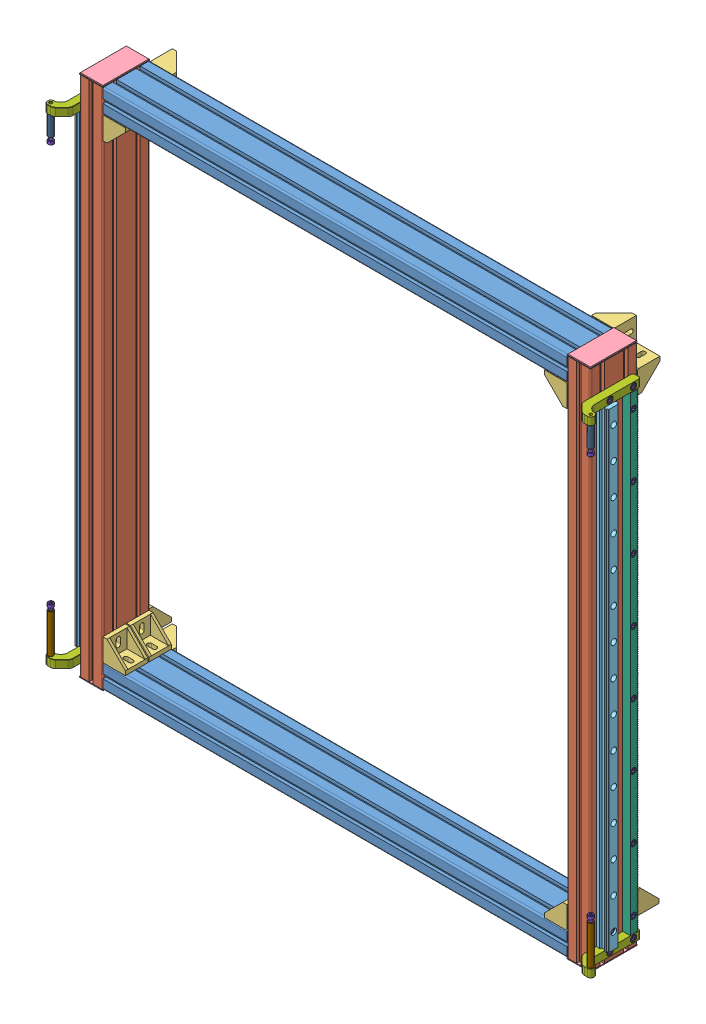
SolidWorks assembly Frame Top Stage, configuration Défaut. Lengths in mm.
Overall size (1047.13 1003 167.07).
94 component instances, 10 part files, 181 mates.
Components (placement in the parent):
- Frame X Top-1: Frame X Top [Défaut] at (-67 22.5 45) x (0 1 0) z (-1 0 0) size (45 90 888)
- Frame Y Top-1: Frame Y Top [Défaut] at (-3.2889 -2 75.8154) x (-1 0 0) z (0 -1 0) size (45 90 998)
- Frame X Top-2: Frame X Top [Défaut] at (-67 975.5 45) x (0 1 0) z (-1 0 0) size (45 90 888)
- Frame Y Top-2: Frame Y Top [Défaut] at (929.7111 -2 75.8154) x (-1 0 0) z (0 -1 0) size (45 90 998)
- nervure-1: nervure [Default] at (45 45 47) size (43 43 43)
- nervure-2: nervure [Default] at (45 953 47) x (0 -1 0) z (0 0 1) size (43 43 43)
- nervure-3: nervure [Default] at (933 45 47) x (0 1 0) z (0 0 1) size (43 43 43)
- nervure-4: nervure [Default] at (933 953 47) x (-1 0 0) z (0 0 1) size (43 43 43)
- nervure-5: nervure [Default] at (45 953 2) x (0 -1 0) z (0 0 1) size (43 43 43)
- nervure-6: nervure [Default] at (933 953 2) x (-1 0 0) z (0 0 1) size (43 43 43)
- nervure-7: nervure [Default] at (933 45 2) x (0 1 0) z (0 0 1) size (43 43 43)
- nervure-8: nervure [Default] at (45 45 2) size (43 43 43)
- Alu Profile End Cap 45x90-1: Alu Profile End Cap 45x90 [Défaut] at (22.5 0 45) x (0 0 1) z (0 -1 0) size (90 45 12.5)
- Alu Profile End Cap 45x90-5: Alu Profile End Cap 45x90 [Défaut] at (22.5 998 45) x (0 0 1) z (0 1 0) size (90 45 12.5)
- Alu Profile End Cap 45x90-6: Alu Profile End Cap 45x90 [Défaut] at (955.5 998 45) x (0 0 1) z (0 1 0) size (90 45 12.5)
- Alu Profile End Cap 45x90-4: Alu Profile End Cap 45x90 [Défaut] at (955.5 0 45) x (0 0 1) z (0 -1 0) size (90 45 12.5)
- nervure-9: nervure [Default] at (45 0 0) x (1 0 0) z (0 1 0) size (43 43 43)
- nervure-10: nervure [Default] at (43 45 0) x (0 1 0) z (-1 0 0) size (43 43 43)
- nervure-11: nervure [Default] at (933 45 0) x (-1 0 0) z (0 -1 0) size (43 43 43)
- nervure-12: nervure [Default] at (976 45 0) x (0 1 0) z (-1 0 0) size (43 43 43)
- nervure-13: nervure [Default] at (935 953 0) x (0 -1 0) z (1 0 0) size (43 43 43)
- nervure-14: nervure [Default] at (933 998 0) x (-1 0 0) z (0 -1 0) size (43 43 43)
- nervure-15: nervure [Default] at (2 953 0) x (0 -1 0) z (1 0 0) size (43 43 43)
- nervure-16: nervure [Default] at (45 953 0) x (1 0 0) z (0 1 0) size (43 43 43)
- HGR25-R1000-1: HGR25-R1000 [Default] at (989 485.5 67.5) x (0 0 -1) z (0 -1 0) size (23 22 900)
- Rack-2: Rack [Défaut] at (993 931.8745 23.75) x (0 1 0) z (-1 0 0) size (899.02 15 15)
- HGR25-R1000-2: HGR25-R1000 [Default] at (-11 485.5 67.5) x (0 0 -1) z (0 1 0) size (23 22 900)
- Y Axis Stop-1: Y Axis Stop [Défaut] at (979.0859 950.5 84.2092) x (1 0 0) z (0 -1 0) size (34 114.75 15)
- Y Axis Stop-2: Y Axis Stop [Défaut] at (979.0859 35.5 84.2092) x (1 0 0) z (0 -1 0) size (34 114.75 15)
- Y Axis Stop-3: Y Axis Stop [Défaut] at (-1.0859 935.5 84.2092) x (-1 0 0) z (0 1 0) size (34 114.75 15)
- Y Axis Stop-4: Y Axis Stop [Défaut] at (-1.0859 20.5 84.2092) x (-1 0 0) z (0 1 0) size (34 114.75 15)
- socket head cap screw_am-2: socket head cap screw_am [B18.3.1M - 6 x 1.0 x 16 Hex SHCS -- 16NHX] at (-27.5 883 117) x (0 1 0) z (0 0 1) size (22 10 10)
- socket head cap screw_am-3: socket head cap screw_am [B18.3.1M - 6 x 1.0 x 16 Hex SHCS -- 16NHX] at (-27.5 122 117) x (0 -1 0) z (0.064917 0 0.997891) size (22 10 10)
- socket head cap screw_am-4: socket head cap screw_am [B18.3.1M - 6 x 1.0 x 16 Hex SHCS -- 16NHX] at (1005.5 122 117) x (0 -1 0) z (0 0 1) size (22 10 10)
- socket head cap screw_am-5: socket head cap screw_am [B18.3.1M - 6 x 1.0 x 16 Hex SHCS -- 16NHX] at (1005.5 883 117) x (0 1 0) z (0 0 1) size (22 10 10)
- Rack-5: Rack [Défaut] at (-15 39.1255 23.75) x (0 -1 0) z (1 0 0) size (899.02 15 15)
- socket head cap screw_am-6: socket head cap screw_am [B18.3.1M - 6 x 1.0 x 10 Hex SHCS -- 10NHX] at (997 65.5 67.5) x (-1 0 0) z (0 0.924225 0.381849) size (16 10 10)
- socket head cap screw_am-7: socket head cap screw_am [B18.3.1M - 6 x 1.0 x 10 Hex SHCS -- 10NHX] at (997 125.5 67.5) x (-1 0 0) z (0 0.924225 0.381849) size (16 10 10)
- socket head cap screw_am-8: socket head cap screw_am [B18.3.1M - 6 x 1.0 x 10 Hex SHCS -- 10NHX] at (997 185.5 67.5) x (-1 0 0) z (0 0.924225 0.381849) size (16 10 10)
- socket head cap screw_am-9: socket head cap screw_am [B18.3.1M - 6 x 1.0 x 10 Hex SHCS -- 10NHX] at (997 245.5 67.5) x (-1 0 0) z (0 0.924225 0.381849) size (16 10 10)
- socket head cap screw_am-10: socket head cap screw_am [B18.3.1M - 6 x 1.0 x 10 Hex SHCS -- 10NHX] at (997 305.5 67.5) x (-1 0 0) z (0 0.924225 0.381849) size (16 10 10)
- socket head cap screw_am-11: socket head cap screw_am [B18.3.1M - 6 x 1.0 x 10 Hex SHCS -- 10NHX] at (997 365.5 67.5) x (-1 0 0) z (0 0.924225 0.381849) size (16 10 10)
- socket head cap screw_am-12: socket head cap screw_am [B18.3.1M - 6 x 1.0 x 10 Hex SHCS -- 10NHX] at (997 425.5 67.5) x (-1 0 0) z (0 0.924225 0.381849) size (16 10 10)
- socket head cap screw_am-13: socket head cap screw_am [B18.3.1M - 6 x 1.0 x 10 Hex SHCS -- 10NHX] at (997 485.5 67.5) x (-1 0 0) z (0 0.924225 0.381849) size (16 10 10)
- socket head cap screw_am-14: socket head cap screw_am [B18.3.1M - 6 x 1.0 x 10 Hex SHCS -- 10NHX] at (997 545.5 67.5) x (-1 0 0) z (0 0.924225 0.381849) size (16 10 10)
- socket head cap screw_am-15: socket head cap screw_am [B18.3.1M - 6 x 1.0 x 10 Hex SHCS -- 10NHX] at (997 605.5 67.5) x (-1 0 0) z (0 0.924225 0.381849) size (16 10 10)
- socket head cap screw_am-16: socket head cap screw_am [B18.3.1M - 6 x 1.0 x 10 Hex SHCS -- 10NHX] at (997 665.5 67.5) x (-1 0 0) z (0 0.924225 0.381849) size (16 10 10)
- socket head cap screw_am-17: socket head cap screw_am [B18.3.1M - 6 x 1.0 x 10 Hex SHCS -- 10NHX] at (997 725.5 67.5) x (-1 0 0) z (0 0.924225 0.381849) size (16 10 10)
- socket head cap screw_am-18: socket head cap screw_am [B18.3.1M - 6 x 1.0 x 10 Hex SHCS -- 10NHX] at (997 785.5 67.5) x (-1 0 0) z (0 0.924225 0.381849) size (16 10 10)
- socket head cap screw_am-19: socket head cap screw_am [B18.3.1M - 6 x 1.0 x 10 Hex SHCS -- 10NHX] at (997 845.5 67.5) x (-1 0 0) z (0 0.924225 0.381849) size (16 10 10)
- socket head cap screw_am-20: socket head cap screw_am [B18.3.1M - 6 x 1.0 x 10 Hex SHCS -- 10NHX] at (997 905.5 67.5) x (-1 0 0) z (0 0.978734 0.205133) size (16 10 10)
- socket head cap screw_am-21: socket head cap screw_am [B18.3.1M - 6 x 1.0 x 10 Hex SHCS -- 10NHX] at (-19 65.5 67.5) size (16 10 10)
- socket head cap screw_am-22: socket head cap screw_am [B18.3.1M - 6 x 1.0 x 10 Hex SHCS -- 10NHX] at (-19 125.5 67.5) size (16 10 10)
- socket head cap screw_am-23: socket head cap screw_am [B18.3.1M - 6 x 1.0 x 10 Hex SHCS -- 10NHX] at (-19 185.5 67.5) size (16 10 10)
- socket head cap screw_am-24: socket head cap screw_am [B18.3.1M - 6 x 1.0 x 10 Hex SHCS -- 10NHX] at (-19 245.5 67.5) size (16 10 10)
- socket head cap screw_am-25: socket head cap screw_am [B18.3.1M - 6 x 1.0 x 10 Hex SHCS -- 10NHX] at (-19 305.5 67.5) size (16 10 10)
- socket head cap screw_am-26: socket head cap screw_am [B18.3.1M - 6 x 1.0 x 10 Hex SHCS -- 10NHX] at (-19 365.5 67.5) size (16 10 10)
- socket head cap screw_am-27: socket head cap screw_am [B18.3.1M - 6 x 1.0 x 10 Hex SHCS -- 10NHX] at (-19 425.5 67.5) size (16 10 10)
- socket head cap screw_am-28: socket head cap screw_am [B18.3.1M - 6 x 1.0 x 10 Hex SHCS -- 10NHX] at (-19 485.5 67.5) size (16 10 10)
- socket head cap screw_am-29: socket head cap screw_am [B18.3.1M - 6 x 1.0 x 10 Hex SHCS -- 10NHX] at (-19 545.5 67.5) size (16 10 10)
- socket head cap screw_am-30: socket head cap screw_am [B18.3.1M - 6 x 1.0 x 10 Hex SHCS -- 10NHX] at (-19 605.5 67.5) size (16 10 10)
- socket head cap screw_am-31: socket head cap screw_am [B18.3.1M - 6 x 1.0 x 10 Hex SHCS -- 10NHX] at (-19 665.5 67.5) size (16 10 10)
- socket head cap screw_am-32: socket head cap screw_am [B18.3.1M - 6 x 1.0 x 10 Hex SHCS -- 10NHX] at (-19 725.5 67.5) size (16 10 10)
- socket head cap screw_am-33: socket head cap screw_am [B18.3.1M - 6 x 1.0 x 10 Hex SHCS -- 10NHX] at (-19 785.5 67.5) size (16 10 10)
- socket head cap screw_am-34: socket head cap screw_am [B18.3.1M - 6 x 1.0 x 10 Hex SHCS -- 10NHX] at (-19 845.5 67.5) size (16 10 10)
- socket head cap screw_am-35: socket head cap screw_am [B18.3.1M - 6 x 1.0 x 10 Hex SHCS -- 10NHX] at (-19 905.5 67.5) x (1 0 0) z (0 -0.994502 0.104716) size (16 10 10)
- socket head cap screw_am-36: socket head cap screw_am [B18.3.1M - 6 x 1.0 x 16 Hex SHCS -- 16NHX] at (-14.6 65.0096 22.5) size (22 10 10)
- socket head cap screw_am-37: socket head cap screw_am [B18.3.1M - 6 x 1.0 x 16 Hex SHCS -- 16NHX] at (-14.6 185.0096 22.5) size (22 10 10)
- socket head cap screw_am-38: socket head cap screw_am [B18.3.1M - 6 x 1.0 x 16 Hex SHCS -- 16NHX] at (-14.6 305.0096 22.5) size (22 10 10)
- socket head cap screw_am-39: socket head cap screw_am [B18.3.1M - 6 x 1.0 x 16 Hex SHCS -- 16NHX] at (-14.6 425.0096 22.5) size (22 10 10)
- socket head cap screw_am-40: socket head cap screw_am [B18.3.1M - 6 x 1.0 x 16 Hex SHCS -- 16NHX] at (-14.6 545.0096 22.5) size (22 10 10)
- socket head cap screw_am-41: socket head cap screw_am [B18.3.1M - 6 x 1.0 x 16 Hex SHCS -- 16NHX] at (-14.6 665.0096 22.5) size (22 10 10)
- socket head cap screw_am-42: socket head cap screw_am [B18.3.1M - 6 x 1.0 x 16 Hex SHCS -- 16NHX] at (-14.6 785.0096 22.5) size (22 10 10)
- socket head cap screw_am-43: socket head cap screw_am [B18.3.1M - 6 x 1.0 x 16 Hex SHCS -- 16NHX] at (-14.6 905.0096 22.5) x (1 0 0) z (0 0.560816 0.82794) size (22 10 10)
- socket head cap screw_am-44: socket head cap screw_am [B18.3.1M - 6 x 1.0 x 16 Hex SHCS -- 16NHX] at (-14.6 943 22.5) size (22 10 10)
- socket head cap screw_am-45: socket head cap screw_am [B18.3.1M - 6 x 1.0 x 16 Hex SHCS -- 16NHX] at (-14.6 943 67.5) size (22 10 10)
- socket head cap screw_am-46: socket head cap screw_am [B18.3.1M - 6 x 1.0 x 16 Hex SHCS -- 16NHX] at (-14.6 28 67.5) size (22 10 10)
- socket head cap screw_am-47: socket head cap screw_am [B18.3.1M - 6 x 1.0 x 16 Hex SHCS -- 16NHX] at (-14.6 28 22.5) size (22 10 10)
- socket head cap screw_am-48: socket head cap screw_am [B18.3.1M - 6 x 1.0 x 16 Hex SHCS -- 16NHX] at (992.6 943 67.5) x (-1 0 0) z (0 0.924225 0.381849) size (22 10 10)
- socket head cap screw_am-49: socket head cap screw_am [B18.3.1M - 6 x 1.0 x 16 Hex SHCS -- 16NHX] at (992.6 943 22.5) x (-1 0 0) z (0 0.924225 0.381849) size (22 10 10)
- socket head cap screw_am-50: socket head cap screw_am [B18.3.1M - 6 x 1.0 x 16 Hex SHCS -- 16NHX] at (992.6 905.9904 22.5) x (-1 0 0) z (0 0.924225 0.381849) size (22 10 10)
- socket head cap screw_am-51: socket head cap screw_am [B18.3.1M - 6 x 1.0 x 16 Hex SHCS -- 16NHX] at (992.6 785.9904 22.5) x (-1 0 0) z (0 0.924225 0.381849) size (22 10 10)
- socket head cap screw_am-52: socket head cap screw_am [B18.3.1M - 6 x 1.0 x 16 Hex SHCS -- 16NHX] at (992.6 665.9904 22.5) x (-1 0 0) z (0 0.924225 0.381849) size (22 10 10)
- socket head cap screw_am-53: socket head cap screw_am [B18.3.1M - 6 x 1.0 x 16 Hex SHCS -- 16NHX] at (992.6 545.9904 22.5) x (-1 0 0) z (0 0.924225 0.381849) size (22 10 10)
- socket head cap screw_am-54: socket head cap screw_am [B18.3.1M - 6 x 1.0 x 16 Hex SHCS -- 16NHX] at (992.6 425.9904 22.5) x (-1 0 0) z (0 0.924225 0.381849) size (22 10 10)
- socket head cap screw_am-55: socket head cap screw_am [B18.3.1M - 6 x 1.0 x 16 Hex SHCS -- 16NHX] at (992.6 305.9904 22.5) x (-1 0 0) z (0 0.924225 0.381849) size (22 10 10)
- socket head cap screw_am-56: socket head cap screw_am [B18.3.1M - 6 x 1.0 x 16 Hex SHCS -- 16NHX] at (992.6 185.9904 22.5) x (-1 0 0) z (0 0.924225 0.381849) size (22 10 10)
- socket head cap screw_am-57: socket head cap screw_am [B18.3.1M - 6 x 1.0 x 16 Hex SHCS -- 16NHX] at (992.6 65.9904 22.5) x (-1 0 0) z (0 0.924225 0.381849) size (22 10 10)
- socket head cap screw_am-58: socket head cap screw_am [B18.3.1M - 6 x 1.0 x 16 Hex SHCS -- 16NHX] at (992.6 28 67.5) x (-1 0 0) z (0 0.924225 0.381849) size (22 10 10)
- socket head cap screw_am-59: socket head cap screw_am [B18.3.1M - 6 x 1.0 x 16 Hex SHCS -- 16NHX] at (992.6 28 22.5) x (-1 0 0) z (0 0.924225 0.381849) size (22 10 10)
- EndStop Spacer 75mm-1: EndStop Spacer 75mm [Défaut] at (1005.5 35.5 117) x (0.737077 0 0.675809) z (0 1 0) size (10 10 85)
- EndStop Spacer 40mm-1: EndStop Spacer 40mm [Défaut] at (-27.5 935.5 117) x (-0.718383 0 -0.695648) z (0 -1 0) size (10 10 50)
- EndStop Spacer 75mm-2: EndStop Spacer 75mm [Défaut] at (-27.5 35.5 117) x (1 0 0) z (0 1 0) size (10 10 85)
- EndStop Spacer 40mm-2: EndStop Spacer 40mm [Défaut] at (1005.5 935.5 117) x (1 0 0) z (0 -1 0) size (10 10 50)
Mates (geometry in assembly coordinates):
- Coïncidente1: coincident anti-aligned: plane of Frame X Top-1 through (45 0 63.5) normal (0 -1 0); plane of assembly through (0 0 0) normal (0 1 0)
- Coïncidente2: coincident anti-aligned: plane of Frame X Top-1 through (45 3 0) normal (0 0 -1); plane of assembly through (0 0 0) normal (0 0 1)
- Distance1: distance = 45 mm: plane of assembly through (0 0 0) normal (1 0 0); plane of assembly; plane of Frame X Top-1 through (45 3 87) normal (-1 0 0)
- Coïncidente3: coincident aligned: plane of Frame X Top-1 through (45 0 63.5) normal (0 -1 0); plane of Frame Y Top-1 through (42 0 87) normal (0 -1 0)
- Coïncidente4: coincident aligned: plane of Frame X Top-1 through (45 42 90) normal (0 0 1); plane of Frame Y Top-1 through (26.5 0 90) normal (0 0 1)
- Coïncidente5: coincident anti-aligned: plane of Frame X Top-1 through (45 3 87) normal (-1 0 0); plane of Frame Y Top-1 through (45 0 63.5) normal (1 0 0)
- Coïncidente6: coincident aligned: plane of Frame X Top-1 through (45 18.5 90) normal (0 0 1); plane of Frame X Top-2 through (45 971.5 90) normal (0 0 1)
- Coïncidente7: coincident aligned: plane of Frame X Top-1 through (933 3 87) normal (1 0 0); plane of Frame X Top-2 through (933 956 87) normal (1 0 0)
- Coïncidente8: coincident aligned: plane of Frame X Top-1 through (45 18.5 90) normal (0 0 1); plane of Frame Y Top-2 through (936 0 90) normal (0 0 1)
- Coïncidente9: coincident aligned: plane of Frame X Top-1 through (45 0 63.5) normal (0 -1 0); plane of Frame Y Top-2 through (975 0 87) normal (0 -1 0)
- Coïncidente10: coincident anti-aligned: plane of Frame X Top-1 through (933 3 87) normal (1 0 0); plane of Frame Y Top-2 through (933 0 26.5) normal (-1 0 0)
- Coïncidente11: coincident aligned: plane of Frame X Top-2 through (45 998 26.5) normal (0 1 0); plane of Frame Y Top-2 through (975 998 87) normal (0 1 0)
- Coïncidente12: coincident aligned: plane of Frame X Top-1 through (45 42 90) normal (0 0 1); plane of nervure-1 through (45 45 90) normal (0 0 1)
- Coïncidente13: coincident anti-aligned: plane of Frame Y Top-1 through (45 0 87) normal (1 0 0); plane of nervure-1 through (45 88 90) normal (-1 0 0)
- Coïncidente14: coincident anti-aligned: plane of Frame X Top-1 through (45 45 71.5) normal (0 1 0); plane of nervure-1 through (45 45 90) normal (0 -1 0)
- Coïncidente15: coincident aligned: plane of Frame X Top-1 through (45 42 90) normal (0 0 1); plane of nervure-3 through (933 45 90) normal (0 0 1)
- Coïncidente16: coincident aligned: plane of Frame X Top-1 through (45 42 90) normal (0 0 1); plane of nervure-2 through (45 953 90) normal (0 0 1)
- Coïncidente17: coincident aligned: plane of Frame X Top-1 through (45 42 90) normal (0 0 1); plane of nervure-4 through (933 953 90) normal (0 0 1)
- Coïncidente18: coincident anti-aligned: plane of Frame Y Top-2 through (933 0 26.5) normal (-1 0 0); plane of nervure-3 through (933 45 90) normal (1 0 0)
- Coïncidente19: coincident anti-aligned: plane of Frame Y Top-2 through (933 0 26.5) normal (-1 0 0); plane of nervure-4 through (933 910 90) normal (1 0 0)
- Coïncidente20: coincident anti-aligned: plane of Frame X Top-2 through (45 953 63.5) normal (0 -1 0); plane of nervure-2 through (88 953 90) normal (0 1 0)
- Coïncidente21: coincident anti-aligned: plane of Frame X Top-2 through (45 953 63.5) normal (0 -1 0); plane of nervure-4 through (933 953 90) normal (0 1 0)
- Coïncidente22: coincident anti-aligned: plane of Frame X Top-1 through (45 45 26.5) normal (0 1 0); plane of nervure-3 through (890 45 90) normal (0 -1 0)
- Coïncidente23: coincident anti-aligned: plane of Frame Y Top-1 through (45 0 63.5) normal (1 0 0); plane of nervure-2 through (45 953 90) normal (-1 0 0)
- Coïncidente24: coincident anti-aligned: plane of Frame Y Top-1 through (42 0 87) normal (0 -1 0); plane of Alu Profile End Cap 45x90-1 through (22.5 0 45) normal (0 1 0)
- Coaxiale1: concentric anti-aligned: cylinder of Frame Y Top-1 through (22.5 0 67.5) axis (0 1 0) radius 4; cylinder of Alu Profile End Cap 45x90-1 through (22.5 10 67.5) axis (0 -1 0) radius 4
- Coaxiale2: concentric anti-aligned: cylinder of Frame Y Top-1 through (22.5 0 22.5) axis (0 1 0) radius 4; cylinder of Alu Profile End Cap 45x90-1 through (22.5 10 22.5) axis (0 -1 0) radius 4
- Coïncidente25: coincident anti-aligned: plane of Frame Y Top-1 through (42 998 87) normal (0 1 0); plane of Alu Profile End Cap 45x90-5 through (22.5 998 45) normal (0 -1 0)
- Coaxiale3: concentric aligned: cylinder of Frame Y Top-1 through (22.5 0 67.5) axis (0 1 0) radius 4; cylinder of Alu Profile End Cap 45x90-5 through (22.5 988 67.5) axis (0 1 0) radius 4
- Coaxiale4: concentric aligned: cylinder of Frame Y Top-1 through (22.5 0 22.5) axis (0 1 0) radius 4; cylinder of Alu Profile End Cap 45x90-5 through (22.5 988 22.5) axis (0 1 0) radius 4
- Coïncidente26: coincident anti-aligned: plane of Frame X Top-1 through (45 26.5 0) normal (0 0 -1); plane of nervure-9 through (45 43 0) normal (0 0 1)
- Coïncidente27: coincident anti-aligned: plane of Frame X Top-1 through (45 26.5 0) normal (0 0 -1); plane of nervure-10 through (0 45 0) normal (0 0 1)
- Coïncidente28: coincident aligned: plane of Frame X Top-1 through (45 0 18.5) normal (0 -1 0); plane of nervure-9 through (45 0 0) normal (0 -1 0)
- Coïncidente29: coincident anti-aligned: plane of Frame Y Top-1 through (45 0 63.5) normal (1 0 0); plane of nervure-9 through (45 43 -43) normal (-1 0 0)
- Coïncidente30: coincident anti-aligned: plane of Frame X Top-1 through (45 45 26.5) normal (0 1 0); plane of nervure-10 through (0 45 -43) normal (0 -1 0)
- Coïncidente31: coincident aligned: plane of Frame Y Top-1 through (0 0 26.5) normal (-1 0 0); plane of nervure-10 through (0 45 0) normal (-1 0 0)
- Coïncidente32: coincident anti-aligned: plane of Frame X Top-1 through (45 3 0) normal (0 0 -1); plane of nervure-12 through (933 45 0) normal (0 0 1)
- Coïncidente33: coincident anti-aligned: plane of Frame X Top-1 through (45 3 0) normal (0 0 -1); plane of nervure-11 through (933 2 0) normal (0 0 1)
- Coïncidente34: coincident aligned: plane of Frame Y Top-2 through (933 0 26.5) normal (-1 0 0); plane of nervure-12 through (933 45 0) normal (-1 0 0)
- Coïncidente35: coincident anti-aligned: plane of Frame X Top-1 through (45 45 26.5) normal (0 1 0); plane of nervure-12 through (933 45 -43) normal (0 -1 0)
- Coïncidente36: coincident aligned: plane of Frame X Top-1 through (45 45 26.5) normal (0 1 0); plane of nervure-11 through (933 45 0) normal (0 1 0)
- Coïncidente37: coincident anti-aligned: plane of Frame Y Top-2 through (933 0 26.5) normal (-1 0 0); plane of nervure-11 through (933 2 -43) normal (1 0 0)
- Coïncidente39: coincident anti-aligned: plane of Frame Y Top-2 through (978 0 63.5) normal (1 0 0); plane of HGR25-R1000-1 through (978 -14.5 78) normal (-1 0 0)
- Largeur2: width anti-aligned: plane of HGR25-R1000-1 through (979 -14.5 56) normal (0 0 -1); plane of Frame Y Top-2 through (984 -14.5 79) normal (0 0 1); plane of HGR25-R1000-1 through (972 0 63.5) normal (0 0 1); plane of Frame Y Top-2 through (978 0 71.5) normal (0 0 -1)
- Coïncidente40: coincident anti-aligned: plane of Frame Y Top-2 through (978 0 63.5) normal (1 0 0); plane of Rack-2 through (978 931.8745 23.75) normal (-1 0 0)
- Largeur3: width: plane of Frame Y Top-2 through (972 0 18.5) normal (0 0 1); plane of Rack-2 through (978 0 26.5) normal (0 0 -1); cylinder of Frame Y Top-2 through (993 905.9904 22.5) axis (1 0 0) radius 3.3
- Largeur4: width: plane of Frame Y Top-2 through (972 0 18.5) normal (0 0 1); plane of Rack-2 through (978 0 26.5) normal (0 0 -1); cylinder of Frame Y Top-2 through (993 785.9904 22.5) axis (1 0 0) radius 3.3
- Largeur5: width aligned: plane of HGR25-R1000-1 through (978 35.5 188.6837) normal (0 -1 0); plane of Rack-2 through (978 935.5 188.6837) normal (0 1 0); plane of HGR25-R1000-1 through (978 35.9904 28.75) normal (0 -1 0); plane of Rack-2 through (978 935.0096 15.95) normal (0 1 0)
- Coïncidente41: coincident anti-aligned: plane of Frame Y Top-2 through (978 0 63.5) normal (1 0 0); plane of Y Axis Stop-1 through (978 935.5 12.75) normal (-1 0 0)
- Largeur6: width: plane of Frame Y Top-2 through (972 0 63.5) normal (0 0 1); plane of Y Axis Stop-1 through (978 0 71.5) normal (0 0 -1); cylinder of Frame Y Top-2 through (993 943 67.5) axis (1 0 0) radius 3.3
- Largeur7: width: plane of Frame Y Top-2 through (978 0 26.5) normal (0 0 -1); plane of Y Axis Stop-1 through (972 0 18.5) normal (0 0 1); cylinder of Frame Y Top-2 through (993 943 22.5) axis (1 0 0) radius 3.3
- Coïncidente51: coincident anti-aligned: plane of HGR25-R1000-1 through (978 935.5 188.6837) normal (0 1 0); plane of Y Axis Stop-1 through (1005.5 935.5 117) normal (0 -1 0)
- Coaxiale5: concentric anti-aligned: cylinder of Y Axis Stop-3 through (-27.5 950.5 117) axis (0 1 0) radius 2.5; cylinder of socket head cap screw_am-2 through (-27.5 851.25 117) axis (0 -1 0) radius 5
- Distance3: distance = 46.5 mm anti-aligned: plane of Y Axis Stop-3 through (-27.5 935.5 117) normal (0 -1 0); plane of socket head cap screw_am-2 through (-32.5 889 117) normal (0 1 0)
- Coaxiale6: concentric aligned: cone of Y Axis Stop-4 through (-27.5 35.5 117) axis (0 1 0); cylinder of socket head cap screw_am-3 through (-27.5 153.75 117) axis (0 1 0) radius 5
- Distance6: distance = 80.5 mm anti-aligned: plane of Y Axis Stop-4 through (-27.5 35.5 117) normal (0 1 0); plane of socket head cap screw_am-3 through (-22.5105 116 116.6754) normal (0 -1 0)
- Coaxiale7: concentric anti-aligned: cylinder of Y Axis Stop-2 through (1005.5 20.5 117) axis (0 -1 0) radius 2.5; cylinder of socket head cap screw_am-4 through (1005.5 153.75 117) axis (0 1 0) radius 5
- Distance5: distance = 80.5 mm anti-aligned: plane of Y Axis Stop-2 through (1005.5 35.5 117) normal (0 1 0); plane of socket head cap screw_am-4 through (1010.5 116 117) normal (0 -1 0)
- Coaxiale8: concentric anti-aligned: cone of Y Axis Stop-1 through (1005.5 936 117) axis (0 1 0); cylinder of socket head cap screw_am-5 through (1005.5 851.25 117) axis (0 -1 0) radius 5
- Distance4: distance = 46.5 mm anti-aligned: plane of Y Axis Stop-1 through (1005.5 935.5 117) normal (0 -1 0); plane of socket head cap screw_am-5 through (1000.5 889 117) normal (0 1 0)
- Coïncidente47: coincident anti-aligned: plane of Frame Y Top-1 through (0 0 26.5) normal (-1 0 0); plane of Rack-5 through (0 39.1255 23.75) normal (1 0 0)
- Largeur8: width: plane of Frame Y Top-1 through (0 0 18.5) normal (0 0 1); plane of Rack-5 through (6 0 26.5) normal (0 0 -1); cylinder of Frame Y Top-1 through (-15 65.0096 22.5) axis (-1 0 0) radius 3.3
- Largeur9: width: plane of Frame Y Top-1 through (6 0 26.5) normal (0 0 -1); plane of Rack-5 through (0 0 18.5) normal (0 0 1); cylinder of Frame Y Top-1 through (-15 185.0096 22.5) axis (-1 0 0) radius 3.3
- Coïncidente49: coincident aligned: plane of Rack-2 through (978 35.9904 28.75) normal (0 -1 0); plane of Rack-5 through (0 35.9904 15.95) normal (0 -1 0)
- Distance8: distance = 20.5 mm anti-aligned: plane of Y Axis Stop-2 through (1005.5 20.5 117) normal (0 -1 0); plane of Alu Profile End Cap 45x90-4 through (955.5 0 45) normal (0 1 0)
- Coaxiale9: concentric aligned: cylinder of HGR25-R1000-1 through (1000 65.5 67.5) axis (1 0 0) radius 3.5; cylinder of socket head cap screw_am-6 through (1028.75 65.5 67.5) axis (1 0 0) radius 5
- Coïncidente52: coincident anti-aligned: plane of HGR25-R1000-1 through (991 65.5 64) normal (1 0 0); plane of socket head cap screw_am-6 through (991 63.5908 72.1211) normal (-1 0 0)
- Coaxiale10: concentric aligned: cylinder of HGR25-R1000-1 through (1000 125.5 67.5) axis (1 0 0) radius 5.5; cylinder of socket head cap screw_am-7 through (1028.75 125.5 67.5) axis (1 0 0) radius 5
- Coïncidente53: coincident anti-aligned: plane of HGR25-R1000-1 through (991 125.5 64) normal (1 0 0); plane of socket head cap screw_am-7 through (991 123.5908 72.1211) normal (-1 0 0)
- Coaxiale11: concentric aligned: cylinder of HGR25-R1000-1 through (1000 185.5 67.5) axis (1 0 0) radius 5.5; cylinder of socket head cap screw_am-8 through (1028.75 185.5 67.5) axis (1 0 0) radius 5
- Coïncidente54: coincident anti-aligned: plane of HGR25-R1000-1 through (991 185.5 64) normal (1 0 0); plane of socket head cap screw_am-8 through (991 183.5908 72.1211) normal (-1 0 0)
- Coaxiale12: concentric aligned: cylinder of HGR25-R1000-1 through (1000 245.5 67.5) axis (1 0 0) radius 3.5; cylinder of socket head cap screw_am-9 through (1028.75 245.5 67.5) axis (1 0 0) radius 5
- Coïncidente55: coincident anti-aligned: plane of HGR25-R1000-1 through (991 245.5 64) normal (1 0 0); plane of socket head cap screw_am-9 through (991 243.5908 72.1211) normal (-1 0 0)
- Coaxiale13: concentric aligned: cylinder of HGR25-R1000-1 through (1000 305.5 67.5) axis (1 0 0) radius 5.5; cylinder of socket head cap screw_am-10 through (1028.75 305.5 67.5) axis (1 0 0) radius 5
- Coïncidente56: coincident anti-aligned: plane of HGR25-R1000-1 through (991 305.5 64) normal (1 0 0); plane of socket head cap screw_am-10 through (991 303.5908 72.1211) normal (-1 0 0)
- Coaxiale14: concentric aligned: cylinder of HGR25-R1000-1 through (1000 365.5 67.5) axis (1 0 0) radius 5.5; cylinder of socket head cap screw_am-11 through (1028.75 365.5 67.5) axis (1 0 0) radius 5
- Coïncidente57: coincident anti-aligned: plane of HGR25-R1000-1 through (991 365.5 64) normal (1 0 0); plane of socket head cap screw_am-11 through (991 363.5908 72.1211) normal (-1 0 0)
- Coaxiale15: concentric aligned: cylinder of HGR25-R1000-1 through (1000 425.5 67.5) axis (1 0 0) radius 5.5; cylinder of socket head cap screw_am-12 through (1028.75 425.5 67.5) axis (1 0 0) radius 5
- Coïncidente58: coincident anti-aligned: plane of HGR25-R1000-1 through (991 425.5 64) normal (1 0 0); plane of socket head cap screw_am-12 through (991 423.5908 72.1211) normal (-1 0 0)
- Coaxiale16: concentric aligned: cylinder of HGR25-R1000-1 through (1000 485.5 67.5) axis (1 0 0) radius 3.5; cylinder of socket head cap screw_am-13 through (1028.75 485.5 67.5) axis (1 0 0) radius 5
- Coïncidente59: coincident anti-aligned: plane of HGR25-R1000-1 through (991 485.5 64) normal (1 0 0); plane of socket head cap screw_am-13 through (991 483.5908 72.1211) normal (-1 0 0)
- Coaxiale17: concentric aligned: cylinder of HGR25-R1000-1 through (1000 545.5 67.5) axis (1 0 0) radius 5.5; cylinder of socket head cap screw_am-14 through (1028.75 545.5 67.5) axis (1 0 0) radius 5
- Coïncidente60: coincident anti-aligned: plane of HGR25-R1000-1 through (991 545.5 64) normal (1 0 0); plane of socket head cap screw_am-14 through (991 543.5908 72.1211) normal (-1 0 0)
- Coaxiale18: concentric aligned: cylinder of HGR25-R1000-1 through (1000 605.5 67.5) axis (1 0 0) radius 5.5; cylinder of socket head cap screw_am-15 through (1028.75 605.5 67.5) axis (1 0 0) radius 5
- Coïncidente61: coincident anti-aligned: plane of HGR25-R1000-1 through (991 605.5 64) normal (1 0 0); plane of socket head cap screw_am-15 through (991 603.5908 72.1211) normal (-1 0 0)
- Coaxiale19: concentric aligned: cylinder of HGR25-R1000-1 through (1000 665.5 67.5) axis (1 0 0) radius 3.5; cylinder of socket head cap screw_am-16 through (1028.75 665.5 67.5) axis (1 0 0) radius 5
- Coïncidente62: coincident anti-aligned: plane of HGR25-R1000-1 through (991 665.5 64) normal (1 0 0); plane of socket head cap screw_am-16 through (991 663.5908 72.1211) normal (-1 0 0)
- Coaxiale20: concentric aligned: cylinder of HGR25-R1000-1 through (1000 725.5 67.5) axis (1 0 0) radius 5.5; cylinder of socket head cap screw_am-17 through (1028.75 725.5 67.5) axis (1 0 0) radius 5
- Coïncidente63: coincident anti-aligned: plane of HGR25-R1000-1 through (991 725.5 64) normal (1 0 0); plane of socket head cap screw_am-17 through (991 723.5908 72.1211) normal (-1 0 0)
- Coaxiale21: concentric aligned: cylinder of HGR25-R1000-1 through (1000 785.5 67.5) axis (1 0 0) radius 5.5; cylinder of socket head cap screw_am-18 through (1028.75 785.5 67.5) axis (1 0 0) radius 5
- Coïncidente64: coincident anti-aligned: plane of HGR25-R1000-1 through (991 785.5 64) normal (1 0 0); plane of socket head cap screw_am-18 through (991 783.5908 72.1211) normal (-1 0 0)
- Coaxiale22: concentric aligned: cylinder of HGR25-R1000-1 through (1000 845.5 67.5) axis (1 0 0) radius 5.5; cylinder of socket head cap screw_am-19 through (1028.75 845.5 67.5) axis (1 0 0) radius 5
- Coïncidente65: coincident anti-aligned: plane of HGR25-R1000-1 through (991 845.5 64) normal (1 0 0); plane of socket head cap screw_am-19 through (991 843.5908 72.1211) normal (-1 0 0)
- Coaxiale23: concentric aligned: cylinder of HGR25-R1000-1 through (1000 905.5 67.5) axis (1 0 0) radius 5.5; cylinder of socket head cap screw_am-20 through (1028.75 905.5 67.5) axis (1 0 0) radius 5
- Coïncidente66: coincident anti-aligned: plane of HGR25-R1000-1 through (991 905.5 64) normal (1 0 0); plane of socket head cap screw_am-20 through (991 904.4743 72.3937) normal (-1 0 0)
- Coaxiale24: concentric aligned: cylinder of HGR25-R1000-2 through (-22 65.5 67.5) axis (-1 0 0) radius 5.5; cylinder of socket head cap screw_am-21 through (-50.75 65.5 67.5) axis (-1 0 0) radius 5
- Coïncidente67: coincident anti-aligned: plane of HGR25-R1000-2 through (-13 65.5 64) normal (-1 0 0); plane of socket head cap screw_am-21 through (-13 70.5 67.5) normal (1 0 0)
- Coaxiale25: concentric aligned: cylinder of HGR25-R1000-2 through (-22 125.5 67.5) axis (-1 0 0) radius 3.5; cylinder of socket head cap screw_am-22 through (-50.75 125.5 67.5) axis (-1 0 0) radius 5
- Coïncidente68: coincident anti-aligned: plane of HGR25-R1000-2 through (-13 125.5 64) normal (-1 0 0); plane of socket head cap screw_am-22 through (-13 130.5 67.5) normal (1 0 0)
- Coaxiale26: concentric aligned: cylinder of HGR25-R1000-2 through (-22 185.5 67.5) axis (-1 0 0) radius 3.5; cylinder of socket head cap screw_am-23 through (-50.75 185.5 67.5) axis (-1 0 0) radius 5
- Coïncidente69: coincident anti-aligned: plane of HGR25-R1000-2 through (-13 185.5 64) normal (-1 0 0); plane of socket head cap screw_am-23 through (-13 190.5 67.5) normal (1 0 0)
- Coaxiale27: concentric aligned: cylinder of HGR25-R1000-2 through (-22 245.5 67.5) axis (-1 0 0) radius 3.5; cylinder of socket head cap screw_am-24 through (-50.75 245.5 67.5) axis (-1 0 0) radius 5
- Coïncidente70: coincident anti-aligned: plane of HGR25-R1000-2 through (-13 245.5 64) normal (-1 0 0); plane of socket head cap screw_am-24 through (-13 250.5 67.5) normal (1 0 0)
- Coaxiale28: concentric aligned: cylinder of HGR25-R1000-2 through (-22 305.5 67.5) axis (-1 0 0) radius 5.5; cylinder of socket head cap screw_am-25 through (-50.75 305.5 67.5) axis (-1 0 0) radius 5
- Coïncidente71: coincident anti-aligned: plane of HGR25-R1000-2 through (-13 305.5 64) normal (-1 0 0); plane of socket head cap screw_am-25 through (-13 310.5 67.5) normal (1 0 0)
- Coaxiale29: concentric aligned: cylinder of HGR25-R1000-2 through (-22 365.5 67.5) axis (-1 0 0) radius 5.5; cylinder of socket head cap screw_am-26 through (-50.75 365.5 67.5) axis (-1 0 0) radius 5
- Coïncidente72: coincident anti-aligned: plane of HGR25-R1000-2 through (-13 365.5 64) normal (-1 0 0); plane of socket head cap screw_am-26 through (-13 370.5 67.5) normal (1 0 0)
- Coaxiale30: concentric aligned: cylinder of HGR25-R1000-2 through (-22 425.5 67.5) axis (-1 0 0) radius 5.5; cylinder of socket head cap screw_am-27 through (-50.75 425.5 67.5) axis (-1 0 0) radius 5
- Coïncidente73: coincident anti-aligned: plane of HGR25-R1000-2 through (-13 425.5 64) normal (-1 0 0); plane of socket head cap screw_am-27 through (-13 430.5 67.5) normal (1 0 0)
- Coaxiale31: concentric aligned: cylinder of HGR25-R1000-2 through (-22 485.5 67.5) axis (-1 0 0) radius 5.5; cylinder of socket head cap screw_am-28 through (-50.75 485.5 67.5) axis (-1 0 0) radius 5
- Coïncidente74: coincident anti-aligned: plane of HGR25-R1000-2 through (-13 485.5 64) normal (-1 0 0); plane of socket head cap screw_am-28 through (-13 490.5 67.5) normal (1 0 0)
- Coaxiale32: concentric aligned: cylinder of HGR25-R1000-2 through (-22 545.5 67.5) axis (-1 0 0) radius 5.5; cylinder of socket head cap screw_am-29 through (-50.75 545.5 67.5) axis (-1 0 0) radius 5
- Coïncidente75: coincident anti-aligned: plane of HGR25-R1000-2 through (-13 545.5 64) normal (-1 0 0); plane of socket head cap screw_am-29 through (-13 550.5 67.5) normal (1 0 0)
- Coaxiale33: concentric aligned: cylinder of HGR25-R1000-2 through (-22 605.5 67.5) axis (-1 0 0) radius 5.5; cylinder of socket head cap screw_am-30 through (-50.75 605.5 67.5) axis (-1 0 0) radius 5
- Coïncidente76: coincident anti-aligned: plane of HGR25-R1000-2 through (-13 605.5 64) normal (-1 0 0); plane of socket head cap screw_am-30 through (-13 610.5 67.5) normal (1 0 0)
- Coaxiale34: concentric aligned: cylinder of HGR25-R1000-2 through (-22 665.5 67.5) axis (-1 0 0) radius 3.5; cylinder of socket head cap screw_am-31 through (-50.75 665.5 67.5) axis (-1 0 0) radius 5
- Coïncidente77: coincident anti-aligned: plane of HGR25-R1000-2 through (-13 665.5 64) normal (-1 0 0); plane of socket head cap screw_am-31 through (-13 670.5 67.5) normal (1 0 0)
- Coaxiale35: concentric aligned: cylinder of HGR25-R1000-2 through (-22 725.5 67.5) axis (-1 0 0) radius 5.5; cylinder of socket head cap screw_am-32 through (-50.75 725.5 67.5) axis (-1 0 0) radius 5
- Coïncidente78: coincident anti-aligned: plane of HGR25-R1000-2 through (-13 725.5 64) normal (-1 0 0); plane of socket head cap screw_am-32 through (-13 730.5 67.5) normal (1 0 0)
- Coaxiale36: concentric aligned: cylinder of HGR25-R1000-2 through (-22 785.5 67.5) axis (-1 0 0) radius 3.5; cylinder of socket head cap screw_am-33 through (-50.75 785.5 67.5) axis (-1 0 0) radius 5
- Coïncidente79: coincident anti-aligned: plane of HGR25-R1000-2 through (-13 785.5 64) normal (-1 0 0); plane of socket head cap screw_am-33 through (-13 790.5 67.5) normal (1 0 0)
- Coaxiale37: concentric aligned: cylinder of HGR25-R1000-2 through (-22 845.5 67.5) axis (-1 0 0) radius 5.5; cylinder of socket head cap screw_am-34 through (-50.75 845.5 67.5) axis (-1 0 0) radius 5
- Coïncidente80: coincident anti-aligned: plane of HGR25-R1000-2 through (-13 845.5 64) normal (-1 0 0); plane of socket head cap screw_am-34 through (-13 850.5 67.5) normal (1 0 0)
- Coaxiale38: concentric aligned: cylinder of HGR25-R1000-2 through (-22 905.5 67.5) axis (-1 0 0) radius 3.5; cylinder of socket head cap screw_am-35 through (-50.75 905.5 67.5) axis (-1 0 0) radius 5
- Coïncidente81: coincident anti-aligned: plane of HGR25-R1000-2 through (-13 905.5 64) normal (-1 0 0); plane of socket head cap screw_am-35 through (-13 906.0236 72.4725) normal (1 0 0)
- Coaxiale39: concentric aligned: cylinder of Rack-5 through (-15 65.0096 22.5) axis (-1 0 0) radius 3.3; cylinder of socket head cap screw_am-36 through (-46.35 65.0096 22.5) axis (-1 0 0) radius 5
- Coïncidente82: coincident anti-aligned: plane of Rack-5 through (-8.6 61.7096 22.5) normal (-1 0 0); plane of socket head cap screw_am-36 through (-8.6 70.0096 22.5) normal (1 0 0)
- Coaxiale40: concentric aligned: cylinder of Rack-5 through (-15 185.0096 22.5) axis (-1 0 0) radius 5.5; cylinder of socket head cap screw_am-37 through (-46.35 185.0096 22.5) axis (-1 0 0) radius 5
- Coïncidente83: coincident anti-aligned: plane of Rack-5 through (-8.6 181.7096 22.5) normal (-1 0 0); plane of socket head cap screw_am-37 through (-8.6 190.0096 22.5) normal (1 0 0)
- Coaxiale41: concentric aligned: cylinder of Rack-5 through (-15 305.0096 22.5) axis (-1 0 0) radius 3.3; cylinder of socket head cap screw_am-38 through (-46.35 305.0096 22.5) axis (-1 0 0) radius 5
- Coïncidente84: coincident anti-aligned: plane of Rack-5 through (-8.6 301.7096 22.5) normal (-1 0 0); plane of socket head cap screw_am-38 through (-8.6 310.0096 22.5) normal (1 0 0)
- Coaxiale42: concentric aligned: cylinder of Rack-5 through (-15 425.0096 22.5) axis (-1 0 0) radius 3.3; cylinder of socket head cap screw_am-39 through (-46.35 425.0096 22.5) axis (-1 0 0) radius 5
- Coïncidente85: coincident anti-aligned: plane of Rack-5 through (-8.6 421.7096 22.5) normal (-1 0 0); plane of socket head cap screw_am-39 through (-8.6 430.0096 22.5) normal (1 0 0)
- Coaxiale43: concentric aligned: cylinder of Rack-5 through (-15 545.0096 22.5) axis (-1 0 0) radius 3.3; cylinder of socket head cap screw_am-40 through (-46.35 545.0096 22.5) axis (-1 0 0) radius 5
- Coïncidente86: coincident anti-aligned: plane of Rack-5 through (-8.6 541.7096 22.5) normal (-1 0 0); plane of socket head cap screw_am-40 through (-8.6 550.0096 22.5) normal (1 0 0)
- Coaxiale44: concentric aligned: cylinder of Rack-5 through (-15 665.0096 22.5) axis (-1 0 0) radius 5.5; cylinder of socket head cap screw_am-41 through (-46.35 665.0096 22.5) axis (-1 0 0) radius 5
- Coïncidente87: coincident anti-aligned: plane of Rack-5 through (-8.6 661.7096 22.5) normal (-1 0 0); plane of socket head cap screw_am-41 through (-8.6 670.0096 22.5) normal (1 0 0)
- Coaxiale45: concentric aligned: cylinder of Rack-5 through (-15 785.0096 22.5) axis (-1 0 0) radius 5.5; cylinder of socket head cap screw_am-42 through (-46.35 785.0096 22.5) axis (-1 0 0) radius 5
- Coïncidente88: coincident anti-aligned: plane of Rack-5 through (-8.6 781.7096 22.5) normal (-1 0 0); plane of socket head cap screw_am-42 through (-8.6 790.0096 22.5) normal (1 0 0)
- Coaxiale46: concentric aligned: cylinder of Rack-5 through (-15 905.0096 22.5) axis (-1 0 0) radius 3.3; cylinder of socket head cap screw_am-43 through (-46.35 905.0096 22.5) axis (-1 0 0) radius 5
- Coïncidente89: coincident anti-aligned: plane of Rack-5 through (-8.6 901.7096 22.5) normal (-1 0 0); plane of socket head cap screw_am-43 through (-8.6 909.1493 19.6959) normal (1 0 0)
- Coaxiale47: concentric aligned: cylinder of Y Axis Stop-3 through (-15 943 22.5) axis (-1 0 0) radius 3.3; cylinder of socket head cap screw_am-44 through (-46.35 943 22.5) axis (-1 0 0) radius 5
- Coïncidente90: coincident anti-aligned: plane of Y Axis Stop-3 through (-8.6 943 25.8) normal (-1 0 0); plane of socket head cap screw_am-44 through (-8.6 948 22.5) normal (1 0 0)
- Coaxiale48: concentric aligned: cylinder of Y Axis Stop-3 through (-15 943 67.5) axis (-1 0 0) radius 5.5; cylinder of socket head cap screw_am-45 through (-46.35 943 67.5) axis (-1 0 0) radius 5
- Coïncidente91: coincident anti-aligned: plane of Y Axis Stop-3 through (-8.6 943 70.8) normal (-1 0 0); plane of socket head cap screw_am-45 through (-8.6 948 67.5) normal (1 0 0)
- Coaxiale49: concentric aligned: cylinder of Y Axis Stop-4 through (-15 28 67.5) axis (-1 0 0) radius 3.3; cylinder of socket head cap screw_am-46 through (-46.35 28 67.5) axis (-1 0 0) radius 5
- Coïncidente92: coincident anti-aligned: plane of Y Axis Stop-4 through (-8.6 28 70.8) normal (-1 0 0); plane of socket head cap screw_am-46 through (-8.6 33 67.5) normal (1 0 0)
- Coaxiale50: concentric aligned: cylinder of Y Axis Stop-4 through (-15 28 22.5) axis (-1 0 0) radius 3.3; cylinder of socket head cap screw_am-47 through (-46.35 28 22.5) axis (-1 0 0) radius 5
- Coïncidente93: coincident anti-aligned: plane of Y Axis Stop-4 through (-8.6 28 25.8) normal (-1 0 0); plane of socket head cap screw_am-47 through (-8.6 33 22.5) normal (1 0 0)
- Coaxiale51: concentric aligned: cylinder of Y Axis Stop-1 through (993 943 67.5) axis (1 0 0) radius 5.5; cylinder of socket head cap screw_am-48 through (1024.35 943 67.5) axis (1 0 0) radius 5
- Coïncidente94: coincident anti-aligned: plane of Y Axis Stop-1 through (986.6 943 70.8) normal (1 0 0); plane of socket head cap screw_am-48 through (986.6 941.0908 72.1211) normal (-1 0 0)
- Coaxiale52: concentric aligned: cylinder of Y Axis Stop-1 through (993 943 22.5) axis (1 0 0) radius 3.3; cylinder of socket head cap screw_am-49 through (1024.35 943 22.5) axis (1 0 0) radius 5
- Coïncidente95: coincident anti-aligned: plane of Y Axis Stop-1 through (986.6 943 25.8) normal (1 0 0); plane of socket head cap screw_am-49 through (986.6 941.0908 27.1211) normal (-1 0 0)
- Coaxiale53: concentric aligned: cylinder of Rack-2 through (993 905.9904 22.5) axis (1 0 0) radius 3.3; cylinder of socket head cap screw_am-50 through (1024.35 905.9904 22.5) axis (1 0 0) radius 5
- Coïncidente96: coincident anti-aligned: plane of Rack-2 through (986.6 909.2904 22.5) normal (1 0 0); plane of socket head cap screw_am-50 through (986.6 904.0812 27.1211) normal (-1 0 0)
- Coaxiale54: concentric aligned: cylinder of Rack-2 through (993 785.9904 22.5) axis (1 0 0) radius 3.3; cylinder of socket head cap screw_am-51 through (1024.35 785.9904 22.5) axis (1 0 0) radius 5
- Coïncidente97: coincident anti-aligned: plane of Rack-2 through (986.6 789.2904 22.5) normal (1 0 0); plane of socket head cap screw_am-51 through (986.6 784.0812 27.1211) normal (-1 0 0)
- Coaxiale55: concentric aligned: cylinder of Rack-2 through (993 665.9904 22.5) axis (1 0 0) radius 5.5; cylinder of socket head cap screw_am-52 through (1024.35 665.9904 22.5) axis (1 0 0) radius 5
- Coïncidente98: coincident anti-aligned: plane of Rack-2 through (986.6 669.2904 22.5) normal (1 0 0); plane of socket head cap screw_am-52 through (986.6 664.0812 27.1211) normal (-1 0 0)
- Coaxiale56: concentric aligned: cylinder of Rack-2 through (993 545.9904 22.5) axis (1 0 0) radius 3.3; cylinder of socket head cap screw_am-53 through (1024.35 545.9904 22.5) axis (1 0 0) radius 5
- Coïncidente99: coincident anti-aligned: plane of Rack-2 through (986.6 549.2904 22.5) normal (1 0 0); plane of socket head cap screw_am-53 through (986.6 544.0812 27.1211) normal (-1 0 0)
- Coaxiale57: concentric aligned: cylinder of Rack-2 through (993 425.9904 22.5) axis (1 0 0) radius 3.3; cylinder of socket head cap screw_am-54 through (1024.35 425.9904 22.5) axis (1 0 0) radius 5
- Coïncidente100: coincident anti-aligned: plane of Rack-2 through (986.6 429.2904 22.5) normal (1 0 0); plane of socket head cap screw_am-54 through (986.6 424.0812 27.1211) normal (-1 0 0)
- Coaxiale58: concentric aligned: cylinder of Rack-2 through (993 305.9904 22.5) axis (1 0 0) radius 3.3; cylinder of socket head cap screw_am-55 through (1024.35 305.9904 22.5) axis (1 0 0) radius 5
- Coïncidente101: coincident anti-aligned: plane of Rack-2 through (986.6 309.2904 22.5) normal (1 0 0); plane of socket head cap screw_am-55 through (986.6 304.0812 27.1211) normal (-1 0 0)
- Coaxiale59: concentric aligned: cylinder of Rack-2 through (993 185.9904 22.5) axis (1 0 0) radius 5.5; cylinder of socket head cap screw_am-56 through (1024.35 185.9904 22.5) axis (1 0 0) radius 5
- Coïncidente102: coincident anti-aligned: plane of Rack-2 through (986.6 189.2904 22.5) normal (1 0 0); plane of socket head cap screw_am-56 through (986.6 184.0812 27.1211) normal (-1 0 0)
- Coaxiale60: concentric aligned: cylinder of Rack-2 through (993 65.9904 22.5) axis (1 0 0) radius 5.5; cylinder of socket head cap screw_am-57 through (1024.35 65.9904 22.5) axis (1 0 0) radius 5
- Coïncidente103: coincident anti-aligned: plane of Rack-2 through (986.6 69.2904 22.5) normal (1 0 0); plane of socket head cap screw_am-57 through (986.6 64.0812 27.1211) normal (-1 0 0)
- Coaxiale61: concentric aligned: cylinder of Y Axis Stop-2 through (993 28 67.5) axis (1 0 0) radius 5.5; cylinder of socket head cap screw_am-58 through (1024.35 28 67.5) axis (1 0 0) radius 5
- Coïncidente104: coincident anti-aligned: plane of Y Axis Stop-2 through (986.6 28 70.8) normal (1 0 0); plane of socket head cap screw_am-58 through (986.6 26.0908 72.1211) normal (-1 0 0)
- Coaxiale62: concentric aligned: cylinder of Y Axis Stop-2 through (993 28 22.5) axis (1 0 0) radius 3.3; cylinder of socket head cap screw_am-59 through (1024.35 28 22.5) axis (1 0 0) radius 5
- Coïncidente105: coincident anti-aligned: plane of Y Axis Stop-2 through (986.6 28 25.8) normal (1 0 0); plane of socket head cap screw_am-59 through (986.6 26.0908 27.1211) normal (-1 0 0)
- Coaxiale64: concentric anti-aligned: cylinder of Y Axis Stop-1 through (1005.5 935.5 117) axis (0 -1 0) radius 2.5; cylinder of EndStop Spacer 40mm-2 through (1005.5 895.5 117) axis (0 1 0) radius 5
- Coïncidente107: coincident anti-aligned: plane of Y Axis Stop-1 through (1005.5 935.5 117) normal (0 -1 0); plane of EndStop Spacer 40mm-2 through (1005.5 935.5 117) normal (0 1 0)
- Coaxiale65: concentric aligned: cylinder of Y Axis Stop-3 through (-27.5 950.5 117) axis (0 1 0) radius 2.5; cylinder of EndStop Spacer 40mm-1 through (-27.5 895.5 117) axis (0 1 0) radius 5
- Coïncidente108: coincident anti-aligned: plane of Y Axis Stop-3 through (-27.5 935.5 117) normal (0 -1 0); plane of EndStop Spacer 40mm-1 through (-27.5 935.5 117) normal (0 1 0)
- Coaxiale66: concentric aligned: cylinder of Y Axis Stop-2 through (1005.5 20.5 117) axis (0 -1 0) radius 2.5; cylinder of EndStop Spacer 75mm-1 through (1005.5 110.5 117) axis (0 -1 0) radius 5
- Coïncidente109: coincident anti-aligned: plane of Y Axis Stop-2 through (1005.5 35.5 117) normal (0 1 0); plane of EndStop Spacer 75mm-1 through (1005.5 35.5 117) normal (0 -1 0)
- Coaxiale67: concentric anti-aligned: cylinder of Y Axis Stop-4 through (-27.5 35.5 117) axis (0 1 0) radius 2.5; cylinder of EndStop Spacer 75mm-2 through (-27.5 110.5 117) axis (0 -1 0) radius 5
- Coïncidente110: coincident anti-aligned: plane of Y Axis Stop-4 through (-27.5 35.5 117) normal (0 1 0); plane of EndStop Spacer 75mm-2 through (-27.5 35.5 117) normal (0 -1 0)
